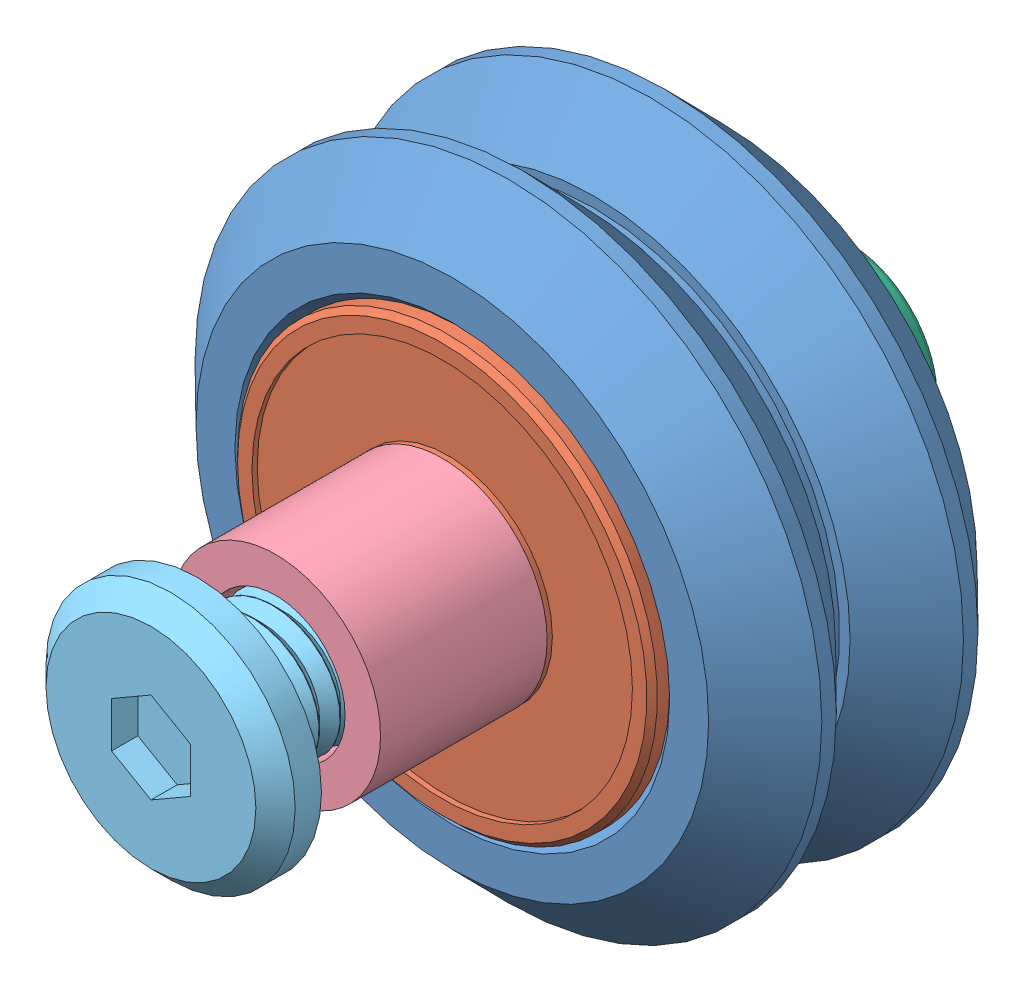
SolidWorks assembly V-Slot Delrin Dual Wheel Assembly, configuration Default. Lengths in mm.
Overall size (23.89 23.89 27.2).
7 component instances, 6 part files, 12 mates.
Components (placement in the parent):
- Delrin Dual V-Wheel-1: Delrin Dual V-Wheel [Default] at (4.1766 13.0717 -11.0846) size (23.89 23.89 10.23)
- Precision Ball Bearing-1: Precision Ball Bearing [Default] at (4.1766 13.0717 -8.0846) x (0 0 -1) z (1 0 0) size (5 16 16)
- Precision Ball Bearing-2: Precision Ball Bearing [Default] at (4.1766 13.0717 -14.0846) x (0 0 -1) z (1 0 0) size (5 16 16)
- 5mm Precision Washer-1: 5mm Precision Washer [Default] at (4.1766 13.0717 -11.5846) x (0 0 1) z (-1 0 0) size (1 10 10)
- .25 Inch Aluminum Spacer-1: .25 Inch Aluminum Spacer [Default] at (4.1766 13.0717 0.7654) x (0 0 -1) z (1 0 0) size (6.35 8 8)
- 5mm Low Profile Socket Head Screw - Multiple Lengths-1: 5mm Low Profile Socket Head Screw - Multiple Lengths [Default] at (4.1766 13.0717 5.5154) x (0 0 -1) z (1 0 0) size (27.2 9.5 9.5)
- Nylon Insert Hex Locknut 5mm-1: Nylon Insert Hex Locknut 5mm [Default] at (4.1766 13.0717 -16.5846) x (-0.923728 -0.383049 0) z (0 0 -1) size (7.68 8.82 4.5)
Mates (geometry in assembly coordinates):
- Coincident1: coincident aligned: plane of Delrin Dual V-Wheel-1 through (4.1766 21.0587 -10.5846) normal (0 0 1); plane of 5mm Precision Washer-1 through (4.1766 13.0717 -10.5846) normal (0 0 1)
- Concentric1: concentric anti-aligned: cylinder of Delrin Dual V-Wheel-1 through (4.1766 13.0717 -5.9696) axis (0 0 1) radius 6.945; cylinder of 5mm Precision Washer-1 through (4.1766 13.0717 -10.5846) axis (0 0 -1) radius 2.5
- Coincident2: coincident anti-aligned: plane of Delrin Dual V-Wheel-1 through (4.1766 21.0587 -10.5846) normal (0 0 1); plane of Precision Ball Bearing-1 through (4.1766 13.0717 -10.5846) normal (0 0 -1)
- Concentric2: concentric aligned: cylinder of Delrin Dual V-Wheel-1 through (4.1766 13.0717 -5.9696) axis (0 0 1) radius 7.987; cylinder of Precision Ball Bearing-1 through (4.1766 13.0717 -10.5846) axis (0 0 1) radius 8
- Coincident3: coincident anti-aligned: plane of Delrin Dual V-Wheel-1 through (4.1766 21.0587 -11.5846) normal (0 0 -1); plane of Precision Ball Bearing-2 through (4.1766 13.0717 -11.5846) normal (0 0 1)
- Concentric3: concentric aligned: cylinder of Delrin Dual V-Wheel-1 through (4.1766 13.0717 -5.9696) axis (0 0 1) radius 7.987; cylinder of Precision Ball Bearing-2 through (4.1766 13.0717 -16.5846) axis (0 0 1) radius 8
- Coincident4: coincident anti-aligned: plane of Precision Ball Bearing-1 through (4.1766 13.0717 -5.5846) normal (0 0 1); plane of .25 Inch Aluminum Spacer-1 through (4.1766 13.0717 -5.5846) normal (0 0 -1)
- Concentric4: concentric anti-aligned: cylinder of Precision Ball Bearing-1 through (4.1766 13.0717 -5.5846) axis (0 0 -1) radius 2.5; cylinder of .25 Inch Aluminum Spacer-1 through (4.1766 13.0717 -5.5846) axis (0 0 1) radius 2.65
- Distance2: distance = 3 mm anti-aligned: plane of 5mm Low Profile Socket Head Screw - Multiple Lengths-1 through (4.1766 15.5717 3.7654) normal (0 0 -1); plane of .25 Inch Aluminum Spacer-1 through (4.1766 13.0717 0.7654) normal (0 0 1)
- Concentric6: concentric aligned: cylinder of .25 Inch Aluminum Spacer-1 through (4.1766 13.0717 -5.5846) axis (0 0 1) radius 4; cylinder of 5mm Low Profile Socket Head Screw - Multiple Lengths-1 through (4.1766 13.0717 5.5154) axis (0 0 1) radius 4.75
- Coincident7: coincident anti-aligned: plane of Precision Ball Bearing-2 through (4.1766 13.0717 -16.5846) normal (0 0 -1); plane of Nylon Insert Hex Locknut 5mm-1 through (4.1766 13.0717 -16.5846) normal (0 0 1)
- Concentric7: concentric anti-aligned: cylinder of 5mm Low Profile Socket Head Screw - Multiple Lengths-1 through (4.1766 13.0717 5.5154) axis (0 0 1) radius 4.75; cylinder of Nylon Insert Hex Locknut 5mm-1 through (4.1766 13.0717 -16.5846) axis (0 0 -1) radius 2.5
